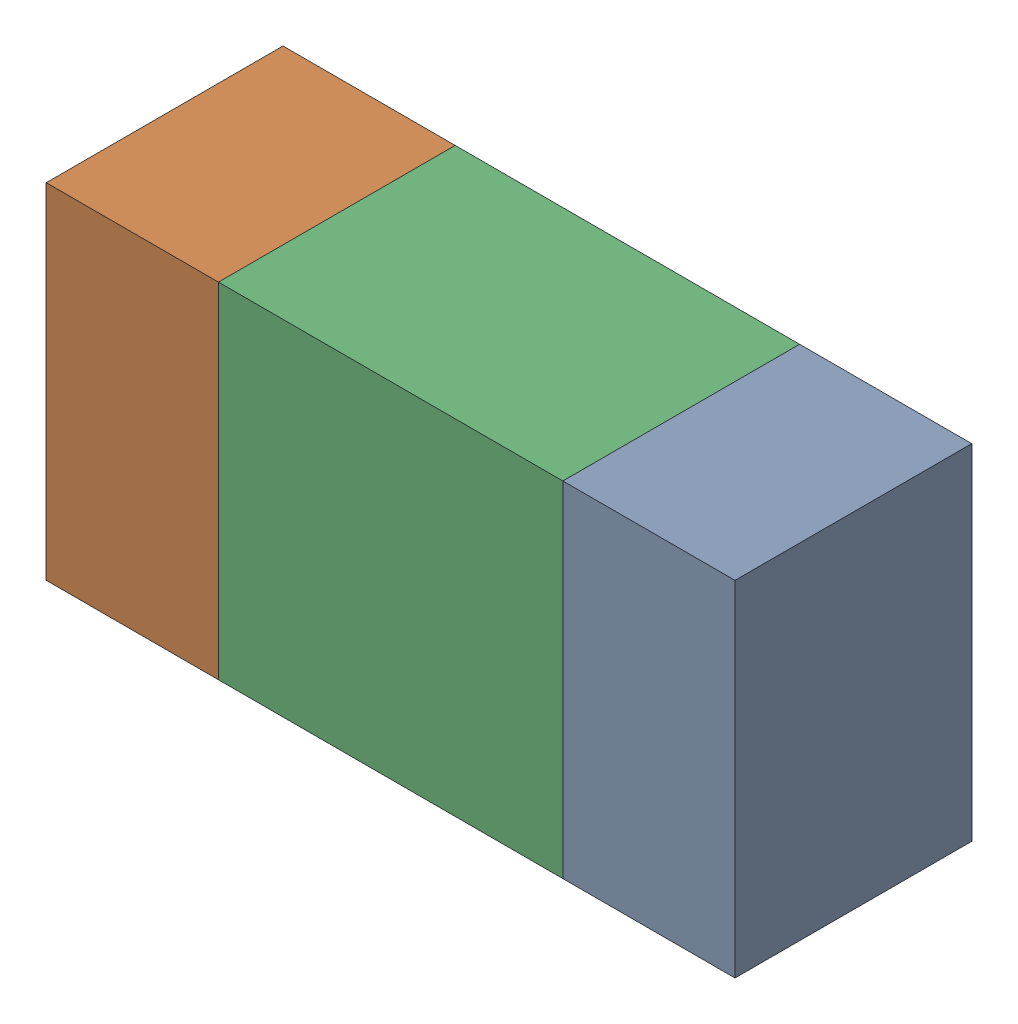
SolidWorks assembly R2, configuration ﾃﾞﾌｫﾙﾄ. Lengths in mm.
Overall size (1.6 0.8 0.55).
6 component instances, 2 part files, 0 mates.
Components (placement in the parent):
- 689261512-1: 689261512 [ﾃﾞﾌｫﾙﾄ] at (62.9999 37.7999 0) size (0.4 0.8 0.55)
  - Extruded_32-1: Extruded_32 [ﾃﾞﾌｫﾙﾄ] at origin size (0.4 0.8 0.55)
- 689261512-2: 689261512 [ﾃﾞﾌｫﾙﾄ] at (61.7999 37.7999 0) size (0.4 0.8 0.55)
  - Extruded_32-1: Extruded_32 [ﾃﾞﾌｫﾙﾄ] at origin size (0.4 0.8 0.55)
- 689261648-1: 689261648 [ﾃﾞﾌｫﾙﾄ] at (62.4 37.7999 0) size (0.8 0.8 0.55)
  - Extruded_33-1: Extruded_33 [ﾃﾞﾌｫﾙﾄ] at origin size (0.8 0.8 0.55)
